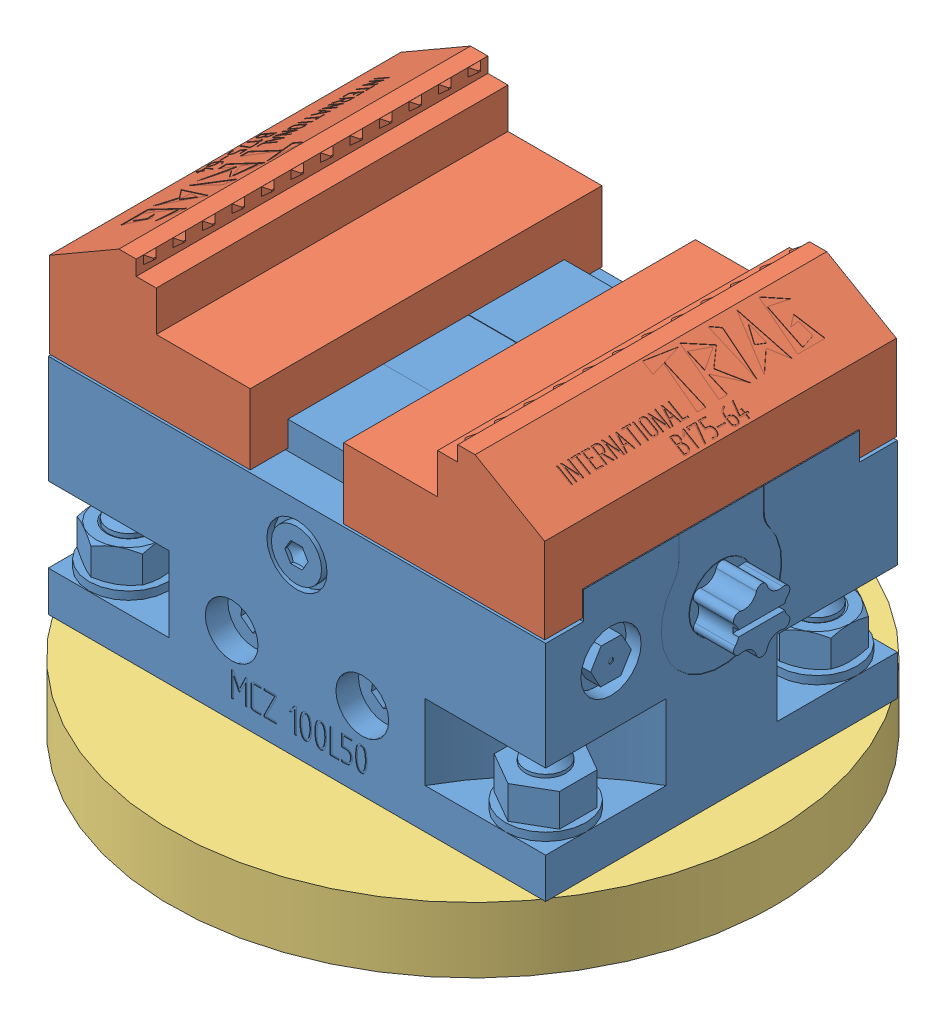
SolidWorks assembly ETAU 44-64mm, configuration Défaut. Lengths in mm.
Overall size (120 83 120).
4 component instances, 3 part files, 11 mates.
Components (placement in the parent):
- Copie de MCZ 100L50_KS^ETAU 44-64mm-1: Copie de MCZ 100L50_KS^ETAU 44-64mm [Défaut] at (0 0 30) size (107 62 70.1) (virtual)
- Copie de B175-64_KS^ETAU 44-64mm-1: Copie de B175-64_KS^ETAU 44-64mm [Défaut] at (41.55 43.436 0) x (0 0 -1) z (0 1 0) size (70 40 25) (virtual)
- Copie de B175-64_KS^ETAU 44-64mm-2: Copie de B175-64_KS^ETAU 44-64mm [Défaut] at (-41.55 43.436 0) x (0 0 1) z (0 1 0) size (70 40 25) (virtual)
- Copie de BASE ADAPT^ETAU 44-64mm-1: Copie de BASE ADAPT^ETAU 44-64mm [Défaut] at (0 -24.064 0) x (1 0 0) z (0 -1 0) size (120 120 13) (virtual)
Mates (geometry in assembly coordinates):
- Coïncidente1: coincident aligned: plane of Copie de MCZ 100L50_KS^ETAU 44-64mm-1 through (0 0 30) normal (1 0 0); plane of assembly through (0 0 0) normal (1 0 0)
- Coïncidente3: coincident aligned: plane of Copie de MCZ 100L50_KS^ETAU 44-64mm-1 through (0 0 0) normal (0 0 1); plane of assembly through (0 0 0) normal (0 0 1)
- Coïncidente4: coincident aligned: plane of Copie de MCZ 100L50_KS^ETAU 44-64mm-1 through (0 0 30) normal (0 1 0); plane of assembly through (0 0 0) normal (0 1 0)
- Coïncidente5: coincident anti-aligned: plane of Copie de B175-64_KS^ETAU 44-64mm-1 through (41.55 43.436 0) normal (0 0 -1); plane of assembly through (0 0 0) normal (0 0 1)
- Coïncidente6: coincident aligned: plane of Copie de B175-64_KS^ETAU 44-64mm-2 through (-41.55 43.436 0) normal (0 0 1); plane of assembly through (0 0 0) normal (0 0 1)
- Coïncidente7: coincident anti-aligned: plane of Copie de MCZ 100L50_KS^ETAU 44-64mm-1 through (49 25.936 0) normal (0 1 0); plane of Copie de B175-64_KS^ETAU 44-64mm-1 through (43.6 25.936 18.15) normal (0 -1 0)
- Coïncidente9: coincident anti-aligned: plane of Copie de MCZ 100L50_KS^ETAU 44-64mm-1 through (49 25.936 0) normal (0 1 0); plane of Copie de B175-64_KS^ETAU 44-64mm-2 through (-43.6 25.936 -18.15) normal (0 -1 0)
- Symétrique1: symmetric aligned: plane of Copie de MCZ 100L50_KS^ETAU 44-64mm-1 through (0 0 30) normal (1 0 0); plane of Copie de B175-64_KS^ETAU 44-64mm-1 through (32 46.086 38.5) normal (-1 0 0); plane of Copie de B175-64_KS^ETAU 44-64mm-2 through (-32 46.086 -38.5) normal (1 0 0)
- Distance1: distance = 64 mm anti-aligned: plane of Copie de B175-64_KS^ETAU 44-64mm-1 through (32 46.086 38.5) normal (-1 0 0); plane of Copie de B175-64_KS^ETAU 44-64mm-2 through (-32 46.086 -38.5) normal (1 0 0)
- Coïncidente10: coincident anti-aligned: plane of Copie de MCZ 100L50_KS^ETAU 44-64mm-1 through (10 -24.064 0) normal (0 -1 0); plane of Copie de BASE ADAPT^ETAU 44-64mm-1 through (0 -24.064 0) normal (0 1 0)
- Coaxiale1: concentric anti-aligned: cylinder of Copie de MCZ 100L50_KS^ETAU 44-64mm-1 through (0 -22.064 0) axis (0 -1 0) radius 11.7378; cylinder of Copie de BASE ADAPT^ETAU 44-64mm-1 through (0 -37.064 0) axis (0 1 0) radius 60
